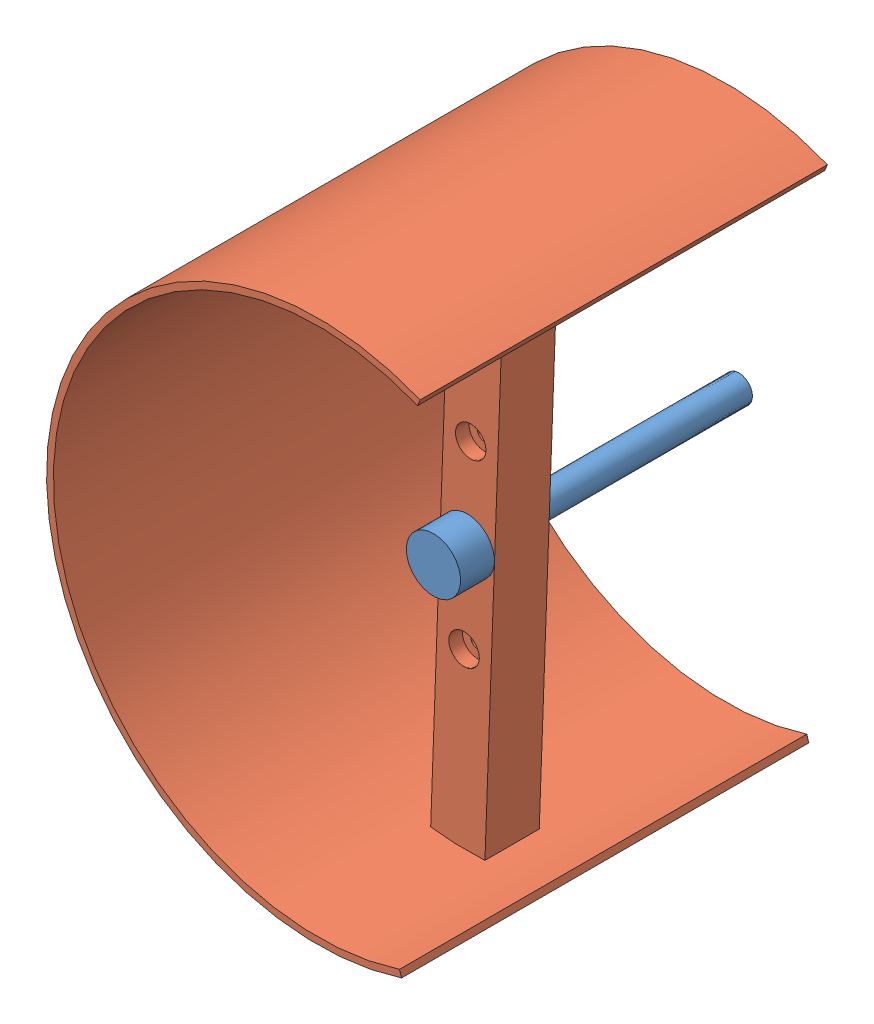
SolidWorks assembly Assemblage6, configuration Défaut. Lengths in mm.
Overall size (82.19 92.12 62).
2 component instances, 2 part files, 2 mates.
Components (placement in the parent):
- Pièce-pour_meca_3d-1: Pièce-pour_meca_3d [Défaut] at (-102.9032 2.1314 17.5) size (8 8 45)
- Cylindre4_20181203-1: Cylindre4_20181203 [Défaut] at (-108.3367 -37.197 -20.5) x (0.999339 -0.036357 0) z (0 0 1) size (79 89.3 60)
Mates (geometry in assembly coordinates):
- Coaxiale2: concentric: cylinder of Pièce-pour_meca_3d-1 through (-102.9032 2.1314 -22.5) axis (0 0 1) radius 2; cylinder of Cylindre4_20181203-1 through (-102.9032 2.1314 17.5) axis (0 0 -1) radius 2
- Coïncidente2: coincident: plane of Pièce-pour_meca_3d-1 through (-102.9032 2.1314 17.5) normal (0 0 -1); plane of Cylindre4_20181203-1 through (-102.9032 2.1314 17.5) normal (0 0 1)
